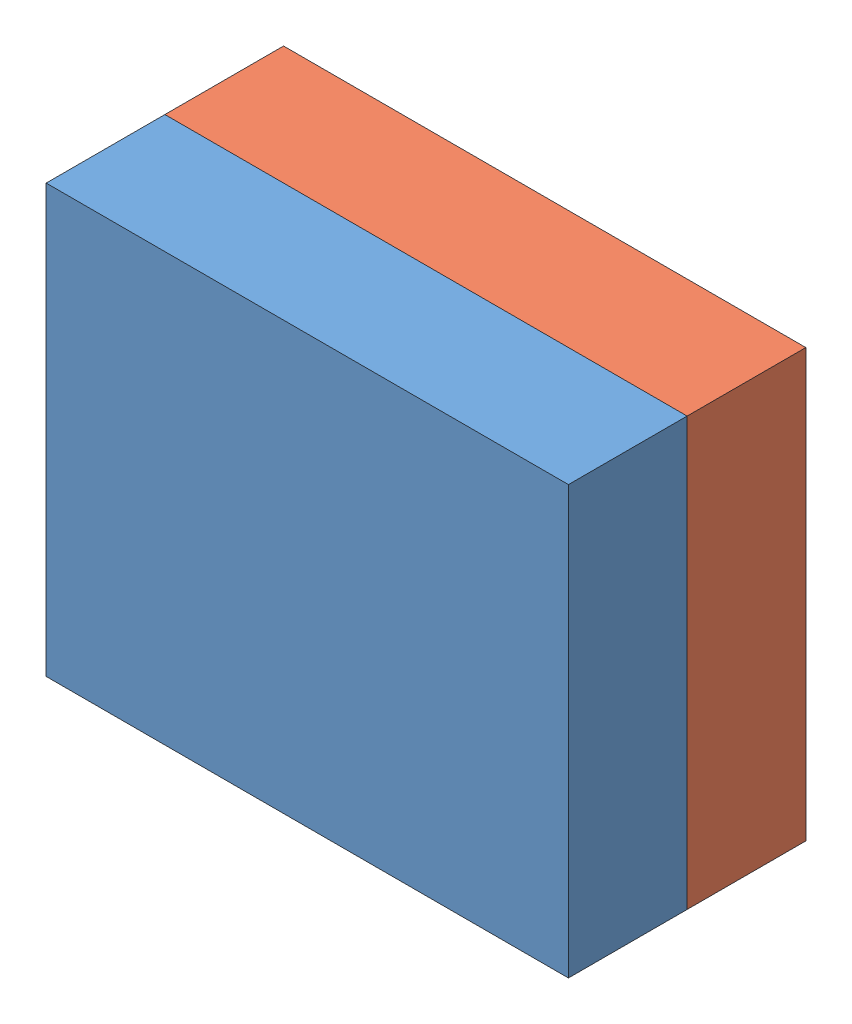
SolidWorks assembly Montagem Bloco, configuration Valor predeterminado. Lengths in mm.
Overall size (220 180 100).
4 component instances, 3 part files, 9 mates.
Components (placement in the parent):
- Cavidade Superior-1: Cavidade Superior [Valor predeterminado] at (24.7163 -116.8903 25) size (220 180 50)
- Cavidade Inferior-1: Cavidade Inferior [Valor predeterminado] at (24.7163 63.1097 -25) size (220 180 50.19)
- Isolador com Contracao-1: Isolador com Contracao [Valor predeterminado] at (24.7163 -8.3903 -25) size (69.01 51.5 51.5)
- Isolador com Contracao-2: Isolador com Contracao [Valor predeterminado] at (24.7163 -96.8903 -25) x (-1 0 0) z (0 0 -1) size (69.01 51.5 51.5)
Mates (geometry in assembly coordinates):
- Coincidente9: coincident aligned: plane of Cavidade Superior-1 through (-85.2837 -116.8903 -25) normal (0 -1 0); plane of Cavidade Inferior-1 through (-85.2837 -116.8903 -75) normal (0 -1 0)
- Coincidente10: coincident anti-aligned: plane of Cavidade Superior-1 through (24.7163 -116.8903 -25) normal (0 0 -1); plane of Cavidade Inferior-1 through (24.7163 63.1097 -25) normal (0 0 1)
- Coincidente11: coincident aligned: plane of Cavidade Superior-1 through (-85.2837 63.1097 -25) normal (-1 0 0); plane of Cavidade Inferior-1 through (-85.2837 63.1097 -75) normal (-1 0 0)
- Distância6: distance = 20 mm aligned: plane of Cavidade Superior-1 through (-85.2837 63.1097 -25) normal (0 1 0); plane of Isolador com Contracao-1 through (24.7163 43.1097 -25) normal (0 1 0)
- Concêntrico1: concentric aligned: circle of Isolador com Contracao-1; circle of Isolador com Contracao-2
- Coincidente15: coincident aligned: plane of Cavidade Inferior-1 through (24.7163 63.1097 -25) normal (0 0 1); plane of Isolador com Contracao-1 through (24.7163 -8.3903 -25) normal (0 0 1)
- Distância5: distance = 66.74 mm aligned: plane of Cavidade Superior-1 through (-85.2837 63.1097 -25) normal (-1 0 0); plane of Isolador com Contracao-2 through (-18.5437 -45.3903 -5.43) normal (-1 0 0)
- Distância7: distance = 20 mm aligned: plane of Cavidade Superior-1 through (-85.2837 -116.8903 -25) normal (0 -1 0); plane of Isolador com Contracao-2 through (50.4663 -96.8903 -25) normal (0 -1 0)
- Coincidente18: coincident anti-aligned: plane of Cavidade Inferior-1 through (24.7163 63.1097 -25) normal (0 0 1); plane of Isolador com Contracao-2 through (24.7163 -96.8903 -25) normal (0 0 -1)
